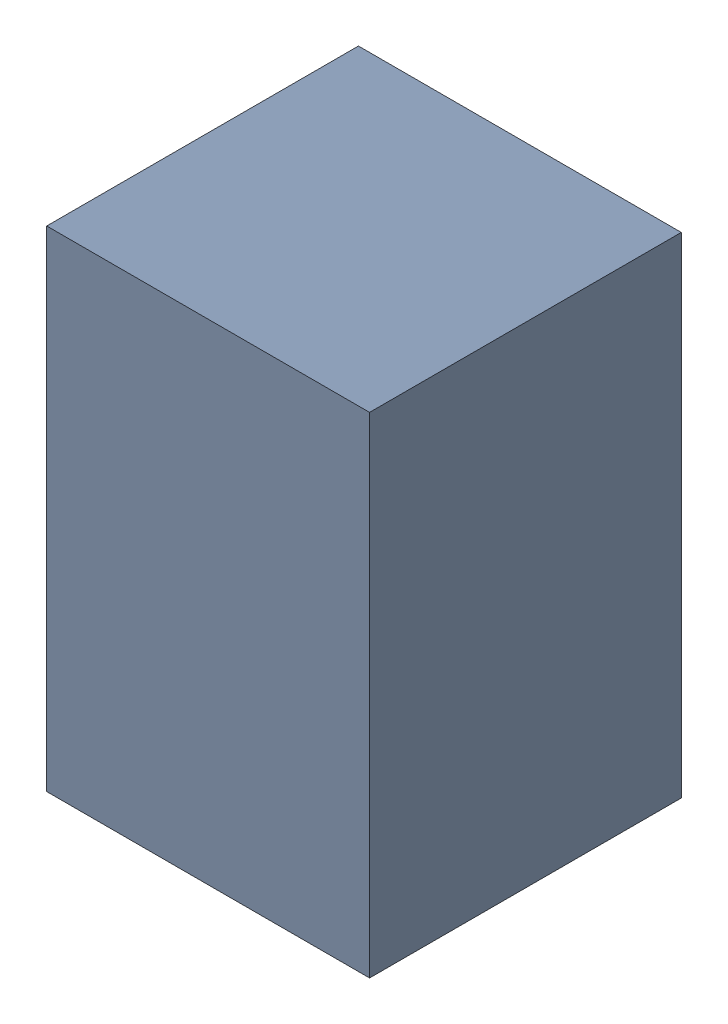
SolidWorks assembly D1-1, configuration Default. Lengths in mm.
Overall size (1.45 2.2 1.4).
2 component instances, 1 part files, 0 mates.
Components (placement in the parent):
- 959209888-1-1: 959209888-1 [Default] at (77.089 89.876 0) size (1.45 2.2 1.4)
  - Extruded-60-1: Extruded-60 [Default] at origin size (1.45 2.2 1.4)
